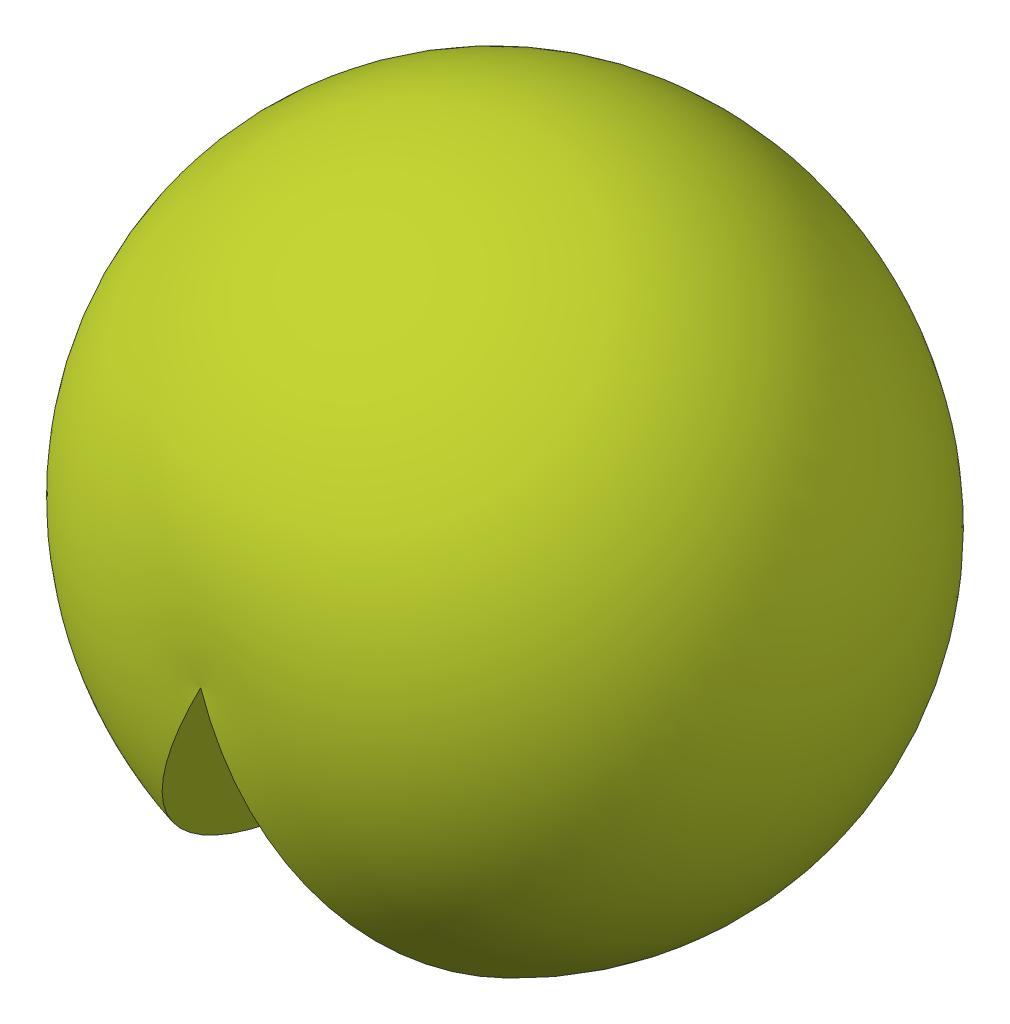
SolidWorks assembly GR6100, configuration 默认. Lengths in mm.
Overall size (7499.03 7331.21 6955.74).
8 component instances, 8 part files, 18 mates.
Components (placement in the parent):
- 底座^GR6100-1: 底座^GR6100 [默认] at (75.3509 21.1464 -642.0001) size (780 905 414.5) (virtual)
- 转座^GR6100-1: 转座^GR6100 [默认] at (27.8308 -667.5 765.9503) x (-1 0 0) z (0 1 0) size (652.72 647.27 822.59) (virtual)
- 大臂^GR6100-1: 大臂^GR6100 [默认] at (-1272.7348 542.4196 1444.4584) x (0 1 0) z (1 0 0) size (355.05 1748.49 308.5) (virtual)
- 小臂^GR6100-1: 小臂^GR6100 [默认] at (233.9555 841.3685 2273.026) x (1 0 0) z (0 -1 0) size (450.9 465.96 2258.5) (virtual)
- 手腕连接体^GR6100-1: 手腕连接体^GR6100 [默认] at (-103.25 2347.5666 2293.7264) x (0 1 0) z (1 0 0) size (100 141.5 106.5) (virtual)
- 手腕^GR6100-1: 手腕^GR6100 [默认] at (-11.8284 2424.5 2171.1853) x (1 0 0) z (0 -1 0) size (78.5 89.5 130.5) (virtual)
- 运动范围图^GR6100-1: 运动范围图^GR6100 [默认] at (0 0 695.3015) x (0 1 0) z (1 0 0) size (7331.21 6955.74 7499.03) (virtual)
- 法兰^GR6100-1: 法兰^GR6100 [默认] at (0 2450.75 2160.5) x (0 -1 0) z (0 0 -1) size (56.6 60 60) (virtual)
Mates (geometry in assembly coordinates):
- 同心1: concentric aligned: cylinder of 底座^GR6100-1 through (0 0 384.5) axis (0 0 -1) radius 200; cylinder of 转座^GR6100-1 through (0 0 440) axis (0 0 -1) radius 200
- 距离1: distance = 2 mm anti-aligned: plane of 转座^GR6100-1 through (-202.4 202.4 386.5) normal (0 0 -1); plane of 底座^GR6100-1 through (202.4 202.4 384.5) normal (0 0 1)
- 同心2: concentric anti-aligned: cylinder of 转座^GR6100-1 through (298.333 300 777) axis (1 0 0) radius 163.75; cylinder of 大臂^GR6100-1 through (468.6933 300 777) axis (-1 0 0) radius 170
- 距离2: distance = 2 mm anti-aligned: plane of 转座^GR6100-1 through (353.9 213.2542 993.9405) normal (1 0 0); plane of 大臂^GR6100-1 through (355.9 127.96 604.96) normal (-1 0 0)
- 同心3: concentric anti-aligned: cylinder of 大臂^GR6100-1 through (437.1055 300 2177) axis (-1 0 0) radius 115; cylinder of 小臂^GR6100-1 through (357.5 300 2177) axis (1 0 0) radius 93
- 距离3: distance = 3.5 mm anti-aligned: plane of 大臂^GR6100-1 through (383.9 416.38 2060.62) normal (-1 0 0); plane of 小臂^GR6100-1 through (387.4 355.8917 2078.0221) normal (1 0 0)
- 同心4: concentric aligned: cylinder of 小臂^GR6100-1 through (136.941 2346 2297) axis (-1 0 0) radius 62.5; cylinder of 手腕连接体^GR6100-1 through (56 2346 2297) axis (-1 0 0) radius 50
- 距离4: distance = 5.5 mm anti-aligned: plane of 小臂^GR6100-1 through (51 2416.1357 2261.2641) normal (-1 0 0); plane of 手腕连接体^GR6100-1 through (56.5 2391.54 2251.46) normal (1 0 0)
- 同心5: concentric anti-aligned: cylinder of 手腕连接体^GR6100-1 through (0 2346 2208.25) axis (0 0 1) radius 40; cylinder of 手腕^GR6100-1 through (0 2346 2210.75) axis (0 0 -1) radius 29
- 距离5: distance = 2.5 mm anti-aligned: plane of 手腕连接体^GR6100-1 through (-38.7767 2388.1145 2208.25) normal (0 0 -1); plane of 手腕^GR6100-1 through (-41.5043 2346 2210.75) normal (0 0 1)
- 同心6: concentric anti-aligned: cylinder of 手腕^GR6100-1 through (0 2431.25 2160.5) axis (0 -1 0) radius 30; cylinder of 法兰^GR6100-1 through (0 2437.75 2160.5) axis (0 1 0) radius 30
- 距离6: distance = 6.5 mm anti-aligned: plane of 手腕^GR6100-1 through (-16.4307 2431.25 2120.8327) normal (0 1 0); plane of 法兰^GR6100-1 through (30.36 2437.75 2190.86) normal (0 -1 0)
- 重合1: coincident: plane of 底座^GR6100-1 through (390 -376.5 0) normal (0 0 -1); point of assembly
- LimitAngle2: limit planar angle = 0 rad aligned: plane of 转座^GR6100-1 through (52 -275 505.6694) normal (0 -1 0); plane of 底座^GR6100-1 through (-210 -418.5 10) normal (0 -1 0)
- LimitAngle3: limit planar angle = 0 rad aligned: plane of 转座^GR6100-1 through (268 300.5 985) normal (0 -1 0); plane of 大臂^GR6100-1 through (283.9 300.5 986.5) normal (0 -1 0)
- LimitAngle5: limit planar angle = 0 rad aligned: plane of 小臂^GR6100-1 through (336.5 300.5 2029) normal (0 -1 0); plane of 大臂^GR6100-1 through (340.4 300.5 2012.5) normal (0 -1 0)
- 同心8: concentric aligned: cylinder of 底座^GR6100-1 through (0 0 384.5) axis (0 0 -1) radius 200; cylinder of 运动范围图^GR6100-1 through (0 0 622.3976) axis (0 0 -1) radius 500
- 平行1: parallel aligned: plane of 运动范围图^GR6100-1 through (0 0 695.3015) normal (1 0 0); plane of assembly through (0 0 0) normal (1 0 0)
